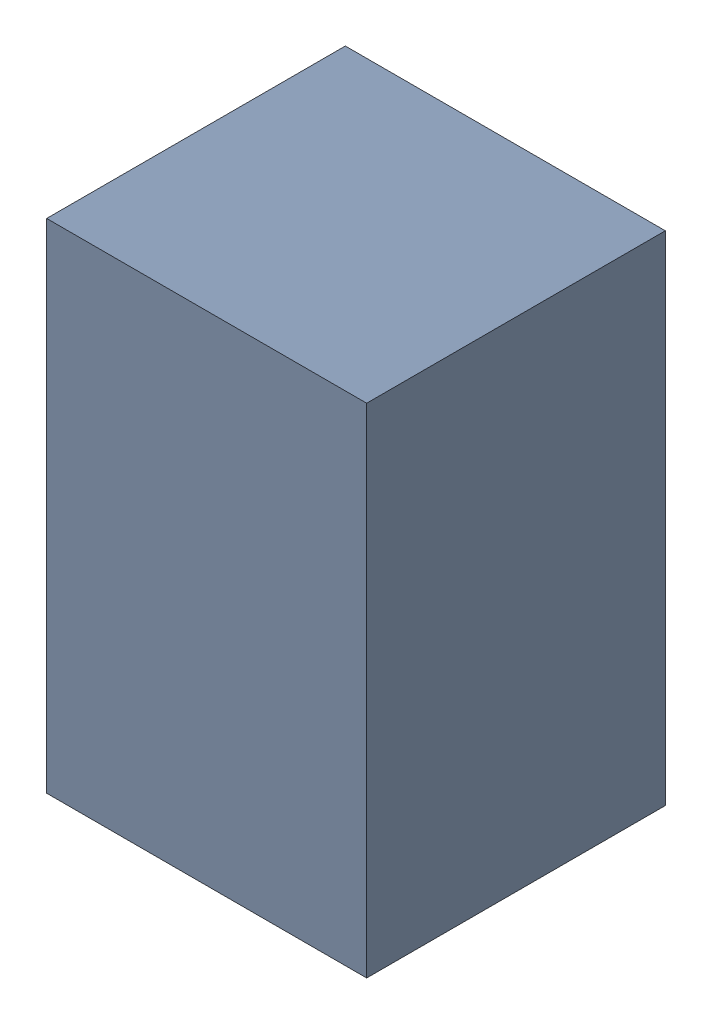
SolidWorks assembly C3, configuration Default. Lengths in mm.
Overall size (1.35 2.1 1.26).
2 component instances, 1 part files, 0 mates.
Components (placement in the parent):
- 407985696-1: 407985696 [Default] at (19.05 61.722 0.0127) size (1.35 2.1 1.26)
  - Extruded_1-1: Extruded_1 [Default] at origin size (1.35 2.1 1.26)
